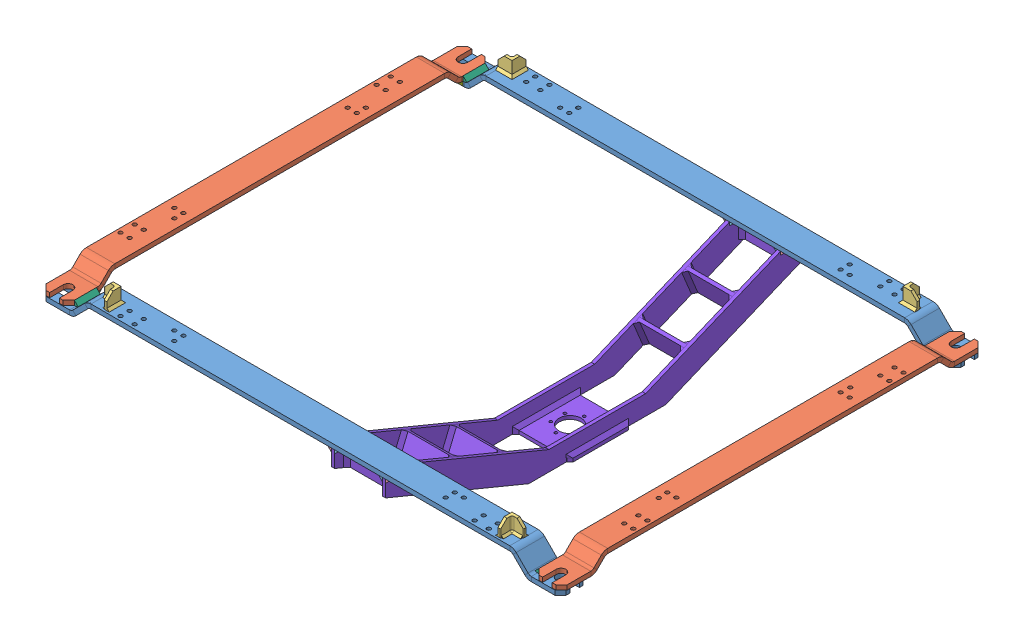
SolidWorks assembly Каркас подъемной платформы сварной, configuration По умолчанию. Lengths in mm.
Overall size (920 166 747).
25 component instances, 8 part files, 59 mates.
Components (placement in the parent):
- Лонжерон  продольный в2-1: Лонжерон  продольный в2 [Левый продольный] at (0 -36 -348.5) size (918 36 50)
- Лонжерон  поперечный в2-1: Лонжерон  поперечный в2 [Правый поперечный] at (435 -28 0) x (0 0 1) z (-1 0 0) size (745 28 50)
- Лонжерон  продольный в2-2: Лонжерон  продольный в2 [Продольный] at (0 -36 348.5) size (918 36 50)
- Лонжерон  поперечный в2-2: Лонжерон  поперечный в2 [Поперечный] at (-435 -28 0) x (0 0 1) z (-1 0 0) size (745 28 50)
- Зуб малый-1: Зуб малый [Со сварными швами<Как обработанный >] at (-345 0 -345) x (0 0 1) z (0 -1 0) size (29 29 25)
- Зуб малый-2: Зуб малый [Со сварными швами<Как обработанный >] at (345 0 -345) x (-1 0 0) z (0 -1 0) size (29 29 25)
- Зуб малый-3: Зуб малый [Со сварными швами<Как обработанный >] at (-345 0 345) x (1 0 0) z (0 -1 0) size (29 29 25)
- Зуб малый-4: Зуб малый [Со сварными швами<Как обработанный >] at (345 0 345) x (0 0 -1) z (0 -1 0) size (29 29 25)
- Св шов держателя 2-1: Св шов держателя 2 [По умолчанию] at (54.5 -8 373.5) x (1 0 0) z (0 0 -1) size (6 6 50)
- Св шов держателя 1-1: Св шов держателя 1 [По умолчанию] at (60.5 -8 373.5) x (1 0 0) z (0 0 -1) size (84 6 22)
- Св шов держателя 1-2: Св шов держателя 1 [По умолчанию] at (144.5 -8 323.5) x (-1 0 0) z (0 0 1) size (84 6 22)
- Св шов держателя 2-2: Св шов держателя 2 [По умолчанию] at (150.5 -8 323.5) x (-1 0 0) z (0 0 1) size (6 6 50)
- Св шов держателя 2-3: Св шов держателя 2 [По умолчанию] at (54.5 -8 -323.5) x (1 0 0) z (0 0 -1) size (6 6 50)
- Св шов держателя 1-3: Св шов держателя 1 [По умолчанию] at (144.5 -8 -373.5) x (-1 0 0) z (0 0 1) size (84 6 22)
- Св шов держателя 1-4: Св шов держателя 1 [По умолчанию] at (60.5 -8 -323.5) x (1 0 0) z (0 0 -1) size (84 6 22)
- Св шов держателя 2-4: Св шов держателя 2 [По умолчанию] at (150.5 -8 -373.5) x (-1 0 0) z (0 0 1) size (6 6 50)
- Св шов лонжерон верхний-1: Св шов лонжерон верхний [По умолчанию] at (0 -36 -373.5) x (-1 0 0) z (0 0 -1) size (6.77 8 39)
- Св шов лонжерон нижний-1: Св шов лонжерон нижний [По умолчанию] at (410 -28 0) x (0 0 1) z (-1 0 0) size (9.72 9.72 39)
- Св шов лонжерон верхний-2: Св шов лонжерон верхний [По умолчанию] at (0 -36 -312.5) size (6.77 8 39)
- Св шов лонжерон нижний-2: Св шов лонжерон нижний [По умолчанию] at (-449 -28 0) x (0 0 1) z (-1 0 0) size (9.72 9.72 39)
- Св шов лонжерон верхний-3: Св шов лонжерон верхний [По умолчанию] at (0 -36 312.5) x (-1 0 0) z (0 0 -1) size (6.77 8 39)
- Св шов лонжерон нижний-3: Св шов лонжерон нижний [По умолчанию] at (449 -28 0) x (0 0 -1) z (1 0 0) size (9.72 9.72 39)
- Св шов лонжерон верхний-4: Св шов лонжерон верхний [По умолчанию] at (0 -36 373.5) size (6.77 8 39)
- Св шов лонжерон нижний-4: Св шов лонжерон нижний [По умолчанию] at (-410 -28 0) x (0 0 -1) z (1 0 0) size (9.72 9.72 39)
- Держатель каркаса подъемной платформы-1: Держатель каркаса подъемной платформы [По умолчанию<Как обработанный >] at (102.5 -141 0) size (108 133 747)
Mates (geometry in assembly coordinates):
- Совпадение1: coincident anti-aligned: plane of Лонжерон  продольный в2-1 through (-468.56 0 -323.5) normal (0 1 0); plane of Зуб малый-1 through (-368.8 0 -348.8) normal (0 -1 0)
- Совпадение2: coincident anti-aligned: plane of Лонжерон  продольный в2-1 through (-468.56 0 -323.5) normal (0 1 0); plane of Зуб малый-2 through (348.8 0 -368.8) normal (0 -1 0)
- Совпадение3: coincident anti-aligned: plane of Лонжерон  продольный в2-2 through (-468.56 0 373.5) normal (0 1 0); plane of Зуб малый-3 through (-348.8 0 368.8) normal (0 -1 0)
- Совпадение4: coincident anti-aligned: plane of Лонжерон  продольный в2-2 through (-468.56 0 373.5) normal (0 1 0); plane of Зуб малый-4 through (368.8 0 348.8) normal (0 -1 0)
- Совпадение5: coincident aligned: plane of Зуб малый-2 through (370 25 -345) normal (0 0 1); plane of Зуб малый-1 through (-345 25 -345) normal (0 0 1)
- Расстояние1: distance = 690 mm anti-aligned: plane of Зуб малый-1 through (-345 25 -370) normal (1 0 0); plane of Зуб малый-2 through (345 25 -345) normal (-1 0 0)
- Совпадение6: coincident aligned: plane of Зуб малый-3 through (-345 25 345) normal (1 0 0); plane of Зуб малый-1 through (-345 25 -370) normal (1 0 0)
- Совпадение7: coincident aligned: plane of Зуб малый-4 through (345 25 370) normal (-1 0 0); plane of Зуб малый-2 through (345 25 -345) normal (-1 0 0)
- Совпадение8: coincident aligned: plane of Зуб малый-3 through (-370 25 345) normal (0 0 -1); plane of Зуб малый-4 through (345 25 345) normal (0 0 -1)
- Концентрический1: concentric aligned: cylinder of Лонжерон  продольный в2-2 through (-435 -36 348.5) axis (0 1 0) radius 8.5; cylinder of Лонжерон  поперечный в2-2 through (-435 -28 348.5) axis (0 1 0) radius 8.5
- Концентрический2: concentric aligned: cylinder of Лонжерон  поперечный в2-1 through (435 -28 348.5) axis (0 1 0) radius 8.5; cylinder of Лонжерон  продольный в2-2 through (435 -36 348.5) axis (0 1 0) radius 8.5
- Концентрический3: concentric aligned: cylinder of Лонжерон  продольный в2-1 through (435 -36 -348.5) axis (0 1 0) radius 8.5; cylinder of Лонжерон  поперечный в2-1 through (435 -28 -348.5) axis (0 1 0) radius 8.5
- Концентрический4: concentric aligned: cylinder of Лонжерон  продольный в2-1 through (-435 -36 -348.5) axis (0 1 0) radius 8.5; cylinder of Лонжерон  поперечный в2-2 through (-435 -28 -348.5) axis (0 1 0) radius 8.5
- Симметричный1: symmetric aligned: plane of Лонжерон  продольный в2-1 through (-9.56 0 -323.5) normal (0 0 1); plane of Лонжерон  продольный в2-2 through (-468.56 0 323.5) normal (0 0 -1); plane of assembly through (0 0 0) normal (0 0 1)
- Симметричный3: symmetric aligned: plane of Лонжерон  поперечный в2-1 through (410 0 -6.2463) normal (-1 0 0); plane of Лонжерон  поперечный в2-2 through (-410 0 -378.7463) normal (1 0 0); plane of assembly through (0 0 0) normal (1 0 0)
- Совпадение9: coincident aligned: plane of Лонжерон  продольный в2-1 through (-468.56 0 -323.5) normal (0 1 0); plane of assembly through (0 0 0) normal (0 1 0)
- Совпадение10: coincident aligned: plane of Лонжерон  продольный в2-1 through (-468.56 0 -323.5) normal (0 1 0); plane of Лонжерон  продольный в2-2 through (-468.56 0 373.5) normal (0 1 0)
- Совпадение11: coincident anti-aligned: plane of Лонжерон  продольный в2-1 through (-459 -28 -323.5) normal (0 1 0); plane of Лонжерон  поперечный в2-2 through (-460 -28 -372.5) normal (0 -1 0)
- Совпадение12: coincident anti-aligned: plane of Лонжерон  продольный в2-1 through (459 -28 -323.5) normal (0 1 0); plane of Лонжерон  поперечный в2-1 through (410 -28 -372.5) normal (0 -1 0)
- Совпадение13: coincident anti-aligned: plane of Лонжерон  продольный в2-1 through (-468.56 0 -323.5) normal (0 1 0); plane of Зуб малый-1 through (-368.8 0 -348.8) normal (0 -1 0)
- Совпадение14: coincident anti-aligned: plane of Лонжерон  продольный в2-1 through (-468.56 0 -323.5) normal (0 1 0); plane of Зуб малый-2 through (348.8 0 -368.8) normal (0 -1 0)
- Совпадение15: coincident anti-aligned: plane of Лонжерон  продольный в2-2 through (-468.56 0 373.5) normal (0 1 0); plane of Зуб малый-4 through (368.8 0 348.8) normal (0 -1 0)
- Совпадение16: coincident anti-aligned: plane of Лонжерон  продольный в2-2 through (-468.56 0 373.5) normal (0 1 0); plane of Зуб малый-3 through (-348.8 0 368.8) normal (0 -1 0)
- Совпадение17: coincident aligned: plane of Зуб малый-1 through (-368.8 25 -350) normal (0 0 -1); plane of Зуб малый-2 through (353.5 25 -350) normal (0 0 -1)
- Совпадение18: coincident aligned: plane of Зуб малый-3 through (-370 25 345) normal (0 0 -1); plane of Зуб малый-4 through (345 25 345) normal (0 0 -1)
- Совпадение19: coincident aligned: plane of Зуб малый-1 through (-345 25 -370) normal (1 0 0); plane of Зуб малый-3 through (-345 25 345) normal (1 0 0)
- Совпадение20: coincident aligned: plane of Зуб малый-2 through (350 25 -368.8) normal (1 0 0); plane of Зуб малый-4 through (350 25 353.5) normal (1 0 0)
- Расстояние3: distance = 700 mm anti-aligned: plane of Зуб малый-2 through (353.5 25 -350) normal (0 0 -1); plane of Зуб малый-4 through (368.8 25 350) normal (0 0 1)
- Симметричный4: symmetric aligned: plane of Зуб малый-2 through (353.5 25 -350) normal (0 0 -1); plane of Зуб малый-4 through (368.8 25 350) normal (0 0 1); plane of assembly through (0 0 0) normal (0 0 1)
- Симметричный5: symmetric aligned: plane of Зуб малый-1 through (-350 25 -353.5) normal (-1 0 0); plane of Зуб малый-2 through (350 25 -368.8) normal (1 0 0); plane of assembly through (0 0 0) normal (1 0 0)
- На месте1: in place: line of Лонжерон  продольный в2-1 through (459 -28 -373.5) axis (0 0 -1); plane of ? through (0 0 -373.5) normal (0 0 -1); moOrthogonalPlaneRef_w of Лонжерон  продольный в2-1 through (459 -28 -373.5) axis (0 0 -1); unknown of ?; line of Лонжерон  продольный в2-1 through (459 -28 -373.5) axis (0 0 -1); plane of ? through (0 0 -373.5) normal (-1 0 0); plane of Лонжерон  продольный в2-1 through (459 -28 -373.5) normal (0 0 -1); unknown of Св шов лонжерон верхний-1
- Совпадение22: coincident aligned: plane of assembly through (459 -28 -373.5) normal (0 0 -1)
- Совпадение23: coincident aligned: moOrthogonalPlaneRef_w of Лонжерон  продольный в2-1 through (0 -36 -373.5) axis (0 1 0); plane of Св шов лонжерон верхний-1
- Совпадение24: coincident anti-aligned: moOrthogonalPlaneRef_w of Лонжерон  продольный в2-1 through (0 -36 -373.5) axis (1 0 0); plane of Св шов лонжерон верхний-1 through (0 -36 -373.5) normal (-1 0 0)
- На месте2: in place: line of Лонжерон  поперечный в2-1 through (410 -20 0) axis (-1 0 0); plane of ? through (410 0 0) normal (-1 0 0); line of Лонжерон  поперечный в2-1 through (410 -20 0) axis (-1 0 0); line of ? through (-50 410 0) axis (0 0 1); line of Лонжерон  поперечный в2-1 through (410 -20 0) axis (-1 0 0); plane of ? through (410 0 0) normal (0 0 1); plane of Лонжерон  поперечный в2-1 through (410 -20 0) normal (-1 0 0); unknown of Св шов лонжерон нижний-1
- Совпадение25: coincident aligned: plane of Лонжерон  поперечный в2-1; plane of Св шов лонжерон нижний-1
- Совпадение26: coincident aligned: moOrthogonalPlaneRef_w of Лонжерон  поперечный в2-1 through (410 -28 0) axis (0 1 0); plane of Св шов лонжерон нижний-1
- Совпадение27: coincident anti-aligned: moOrthogonalPlaneRef_w of Лонжерон  поперечный в2-1 through (410 -28 0) axis (0 0 -1); plane of Св шов лонжерон нижний-1 through (410 -28 0) normal (0 0 1)
- Совпадение28: coincident anti-aligned: plane of Лонжерон  поперечный в2-2 through (-410 -20 -372.5) normal (1 0 0); plane of Св шов лонжерон верхний-2 through (-410 -20 -362.5) normal (-1 0 0)
- Концентрический5: concentric anti-aligned: cylinder of Лонжерон  продольный в2-1 through (-407.5 -20 -297.084) axis (0 0 -1) radius 8; cylinder of Св шов лонжерон верхний-2 through (-407.5 -20 -362.5) axis (0 0 1) radius 8
- Совпадение29: coincident aligned: plane of Лонжерон  продольный в2-1 through (0 -28 -323.5) normal (0 0 1); plane of Св шов лонжерон верхний-2 through (-407.5 -20 -323.5) normal (0 0 1)
- Совпадение30: coincident anti-aligned: plane of Лонжерон  продольный в2-1 through (0 -28 -323.5) normal (0 0 1); plane of Св шов лонжерон нижний-2 through (-410 -28 -323.5) normal (0 0 -1)
- Совпадение31: coincident anti-aligned: plane of Лонжерон  поперечный в2-2 through (-460 -28 -372.5) normal (0 -1 0); plane of Св шов лонжерон нижний-2 through (-410 -28 -323.5) normal (0 1 0)
- Совпадение32: coincident aligned: plane of Лонжерон  поперечный в2-2 through (-410 -20 -372.5) normal (1 0 0); plane of Св шов лонжерон нижний-2 through (-410 -12 -321) normal (1 0 0)
- Расстояние4: distance = 356.5 mm aligned: plane of Держатель каркаса подъемной платформы-1 through (102.5 -141 0) normal (1 0 0); plane of Лонжерон  продольный в2-2 through (459 -28 373.5) normal (1 0 0)
- Совпадение34: coincident anti-aligned: plane of Лонжерон  продольный в2-2 through (-468.56 -8 373.5) normal (0 -1 0); plane of Держатель каркаса подъемной платформы-1 through (144.5 -8 323.5) normal (0 1 0)
- Совпадение35: coincident aligned: plane of Держатель каркаса подъемной платформы-1 through (102.5 -141 0) normal (0 0 1); plane of assembly through (0 0 0) normal (0 0 1)
- Совпадение36: coincident anti-aligned: plane of Держатель каркаса подъемной платформы-1 through (54.5 -135 -54) normal (-1 0 0); plane of Св шов держателя 2-1 through (54.5 -8 323.5) normal (1 0 0)
- Совпадение37: coincident anti-aligned: plane of Св шов держателя 2-1 through (48.5 -8 323.5) normal (0 1 0); plane of Лонжерон  продольный в2-2 through (-468.56 -8 373.5) normal (0 -1 0)
- Совпадение38: coincident aligned: plane of Держатель каркаса подъемной платформы-1 through (54.5 -8 373.5) normal (0 0 1); plane of Св шов держателя 2-1 through (48.5 -8 373.5) normal (0 0 1)
- Совпадение39: coincident anti-aligned: plane of Св шов держателя 1-1 through (60.5 -8 351.5) normal (0 0 -1); plane of Держатель каркаса подъемной платформы-1 through (144.5 -43 351.5) normal (0 0 1)
- Совпадение40: coincident anti-aligned: plane of Св шов держателя 1-1 through (66.5 -8 346.0147) normal (0 1 0); plane of Лонжерон  продольный в2-2 through (-468.56 -8 373.5) normal (0 -1 0)
- Совпадение41: coincident anti-aligned: plane of Держатель каркаса подъемной платформы-1 through (144.5 -135 -54) normal (-1 0 0); plane of Св шов держателя 1-1 through (144.5 -8 351.5) normal (1 0 0)
- Совпадение42: coincident anti-aligned: plane of Лонжерон  продольный в2-2 through (-468.56 -8 373.5) normal (0 -1 0); plane of Св шов держателя 1-2 through (138.5 -8 350.9853) normal (0 1 0)
- Совпадение43: coincident anti-aligned: plane of Св шов держателя 1-2 through (144.5 -8 345.5) normal (0 0 1); plane of Держатель каркаса подъемной платформы-1 through (144.5 -43 345.5) normal (0 0 -1)
- Совпадение44: coincident anti-aligned: plane of Держатель каркаса подъемной платформы-1 through (144.5 -135 -54) normal (-1 0 0); plane of Св шов держателя 1-2 through (144.5 -8 350.9853) normal (1 0 0)
- Совпадение45: coincident anti-aligned: plane of Лонжерон  продольный в2-2 through (-468.56 -8 373.5) normal (0 -1 0); plane of Св шов держателя 2-2 through (156.5 -8 373.5) normal (0 1 0)
- Совпадение46: coincident anti-aligned: plane of Св шов держателя 2-2 through (150.5 -8 373.5) normal (-1 0 0); plane of Держатель каркаса подъемной платформы-1 through (150.5 -135 -54) normal (1 0 0)
- Совпадение47: coincident aligned: plane of Лонжерон  продольный в2-2 through (-9.56 0 373.5) normal (0 0 1); plane of Св шов держателя 2-2 through (156.5 -8 373.5) normal (0 0 1)
